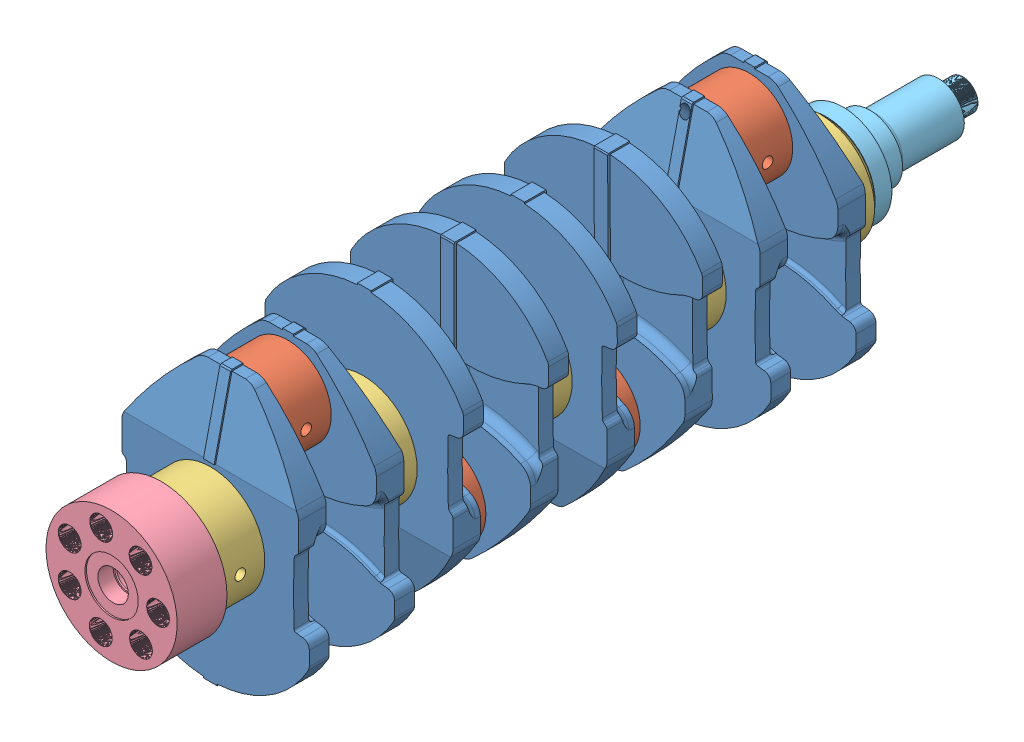
SolidWorks assembly villebrequin, configuration Défaut. Lengths in mm.
Overall size (130.97 174.7 558.17).
19 component instances, 5 part files, 19 mates.
Components (placement in the parent):
- oreille v4-1: oreille v4 [Défaut] at (-9.2136 -215.4022 173.8627) size (130 173.86 18.98)
- cylindre 2 extérieur-2: cylindre 2 extérieur [Défaut] at (-9.3126 52.0265 191.8194) size (57 57 43)
- oreille v4-2: oreille v4 [Défaut] at (-9.225 -215.2711 242.8044) x (-1 0 0) z (0 0 -1) size (130 173.86 18.98)
- oreille v4-5: oreille v4 [Défaut] at (-9.8677 212.5909 343.8134) x (0.999986 0.005361 0) z (0 0 -1) size (130 173.86 18.98)
- cylindre 1 mileu-1: cylindre 1 mileu [Défaut] at (-8.9766 -1.3893 242.7898) size (71 71 32)
- cylindre 2 extérieur-3: cylindre 2 extérieur [Défaut] at (-8.347 -54.7023 292.8284) x (-0.999986 -0.005361 0) z (0 0 1) size (57 57 43)
- oreille v4-6: oreille v4 [Défaut] at (-9.8797 212.722 274.8717) x (-0.999986 -0.005361 0) z (0 0 1) size (130 173.86 18.98)
- oreille v4-7: oreille v4 [Défaut] at (-9.1861 212.9584 375.8383) x (-0.999998 -0.001925 0) z (0 0 1) size (130 173.86 18.98)
- cylindre 2 extérieur-4: cylindre 2 extérieur [Défaut] at (-8.5722 -54.4696 393.795) x (-0.999998 -0.001925 0) z (0 0 1) size (57 57 43)
- oreille v4-8: oreille v4 [Défaut] at (-9.1745 212.8273 444.7801) x (0.999998 0.001925 0) z (0 0 -1) size (130 173.86 18.98)
- cylindre 1 mileu-2: cylindre 1 mileu [Défaut] at (-9.0187 -1.1547 343.7564) x (0.999994 -0.003436 0) z (0 0 1) size (71 71 32)
- cylindre 1 mileu-3: cylindre 1 mileu [Défaut] at (-9.6801 -0.516 444.7442) size (71 71 32)
- oreille v4-11: oreille v4 [Défaut] at (-8.8986 -215.2714 545.7834) x (-1 0 0) z (0 0 -1) size (130 173.86 18.98)
- cylindre 1 mileu-4: cylindre 1 mileu [Défaut] at (-8.6503 -1.3896 545.7688) size (71 71 32)
- cylindre 2 extérieur-6: cylindre 2 extérieur [Défaut] at (-8.9862 52.0261 494.7983) size (57 57 43)
- oreille v4-12: oreille v4 [Défaut] at (-8.8872 -215.4026 476.8416) size (130 173.86 18.98)
- cylindre 1 mileu-5: cylindre 1 mileu [Défaut] at (-8.7358 -1.249 141.727) size (71 71 32)
- cylindre droite 1-1: cylindre droite 1 [Défaut] at (-9.1375 -1.5836 577.5547) size (86 86 32.7)
- piece gauche-1: piece gauche [Défaut] at (-8.9354 -1.1858 141.7088) x (0.997564 -0.069756 0) z (0 0 -1) size (65.34 65.34 89.62)
Mates (geometry in assembly coordinates):
- Verrouiller5: lock: unknown of oreille v4-1; unknown of cylindre 2 extérieur-2
- Verrouiller6: lock: unknown of cylindre 2 extérieur-3; unknown of oreille v4-6
- Verrouiller7: lock: unknown of oreille v4-5; unknown of cylindre 2 extérieur-3
- Verrouiller8: lock: unknown of cylindre 1 mileu-1; unknown of oreille v4-6
- Verrouiller9: lock: unknown of oreille v4-7; unknown of cylindre 1 mileu-2
- Verrouiller10: lock: unknown of cylindre 2 extérieur-4; unknown of oreille v4-8
- Verrouiller11: lock: unknown of oreille v4-7; unknown of cylindre 2 extérieur-4
- Verrouiller15: lock: unknown of cylindre 2 extérieur-6; unknown of oreille v4-12
- Verrouiller16: lock: unknown of cylindre 2 extérieur-6; unknown of oreille v4-12
- Verrouiller17: lock: unknown of oreille v4-11; unknown of cylindre 1 mileu-4
- Verrouiller18: lock: unknown of oreille v4-11; unknown of cylindre 2 extérieur-6
- Verrouiller19: lock: unknown of cylindre 1 mileu-3; unknown of oreille v4-12
- Verrouiller20: lock: unknown of cylindre 1 mileu-4; plane of cylindre droite 1-1 through (0 0 0) normal (0 0 1)
- Verrouiller21: lock: unknown of oreille v4-1; plane of cylindre 1 mileu-5 through (0 0 0) normal (0 0 1)
- Verrouiller23: lock: unknown of oreille v4-8; unknown of cylindre 1 mileu-3
- Verrouiller24: lock: unknown of oreille v4-5; unknown of cylindre 1 mileu-2
- Verrouiller25: lock: unknown of oreille v4-2; unknown of cylindre 1 mileu-1
- Verrouiller26: lock: unknown of cylindre 2 extérieur-2; unknown of oreille v4-2
- Verrouiller27: lock: unknown of cylindre 1 mileu-5; unknown of piece gauche-1
